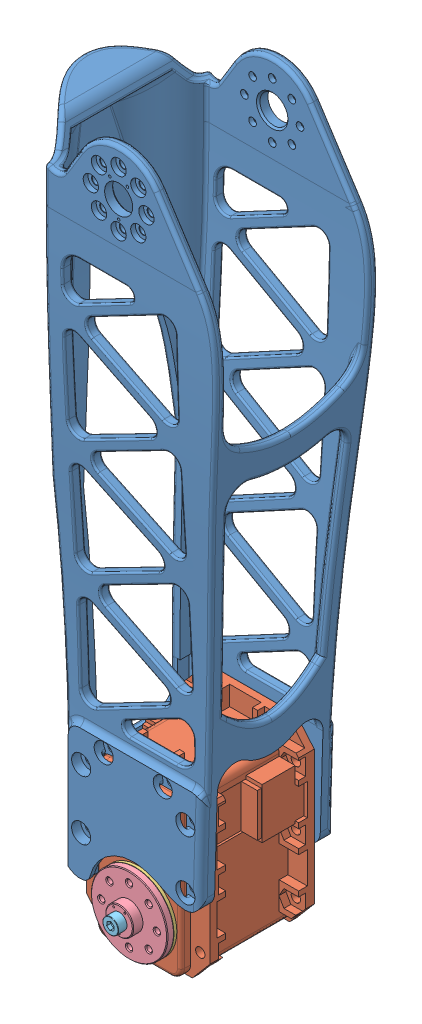
SolidWorks assembly leg, configuration left_MX28. Lengths in mm.
Overall size (66.49 208.53 51.02).
10 component instances, 8 part files, 6 mates.
Components (placement in the parent):
- leg-1: leg [MX28 - MX28] at (-29.7714 -82.05 0) size (66.49 192.04 50.35)
- MX-28-1: MX-28 [U] at (-29.7714 -82.05 0) x (-1 0 0) z (0 0 1) size (35.6 54.13 48.5)
  - dynamixel_x28series-1: dynamixel_x28series [U] at origin size (35.6 50.71 41.85)
  - trust_washer-1: trust_washer [U] at (0 0 18.6) x (-0.666375 -0.745617 0) z (0.745617 -0.666375 0) size (22 0.85 22)
  - HN07-N101-1: HN07-N101 [U] at (0 0 18.5) x (1 0 0) z (0 -1 0) size (22 5.85 22)
  - WB_M2.5x8-1: WB_M2.5x8 [ISO 4762 M2.5 x 8 --- 8N] at (0 0 25.85) x (0 0 -1) z (-0.991137 0.132843 0) size (10.5 4.5 4.5)
  - RX28-CAP-1: RX28-CAP [Défaut] at (0 0 -20.35) x (-0.995735 -0.092256 0) z (0 0 -1) size (7.2 7.2 1.8)
  - MF106ZZ-1: MF106ZZ [Défaut] at (0 0 -20.35) x (0.888333 -0.4592 0) z (-0.4592 -0.888333 0) size (11.2 3 11.2)
  - WB_M2.5x8-3: WB_M2.5x8 [ISO 4762 M2.5 x 8 --- 8N] at (0 0 -22.65) x (0 0 1) z (-0.936501 0.350665 0) size (10.5 4.5 4.5)
  - HN07-i101-1: HN07-i101 [Défaut] at (0 0 -20.5) x (1 0 0) z (0 1 0) size (22 3.05 22)
Mates (geometry in assembly coordinates):
- Coincident1: coincident aligned: plane of leg-1 through (-29.7714 -82.05 0) normal (0 0 1); plane of MX-28-1/dynamixel_x28series-1 through (-29.7714 -82.05 0) normal (0 0 1)
- Coincident2: coincident aligned: line of leg-1 through (-29.7714 -82.05 -29.7913) axis (0 0 1); line of MX-28-1/dynamixel_x28series-1 through (-29.7714 -82.05 -27.2811) axis (0 0 1)
- Parallel1: parallel anti-aligned: plane of leg-1 through (-29.7714 -82.05 0) normal (1 0 0); plane of MX-28-1/dynamixel_x28series-1
- Coincident3: coincident anti-aligned: plane of leg-1 through (-29.7714 -82.05 0) normal (0 0 1); plane of ? through (-3.3974 -51.1818 0) normal (0 0 -1)
- Coincident4: coincident anti-aligned: line of leg-1 through (-29.7714 -82.05 -29.7913) axis (0 0 1); line of ? through (-29.7714 -82.05 27.2811) axis (0 0 -1)
- Coincident5: coincident aligned: plane of leg-1 through (-29.7714 -82.05 0) normal (1 0 0); plane of ?
